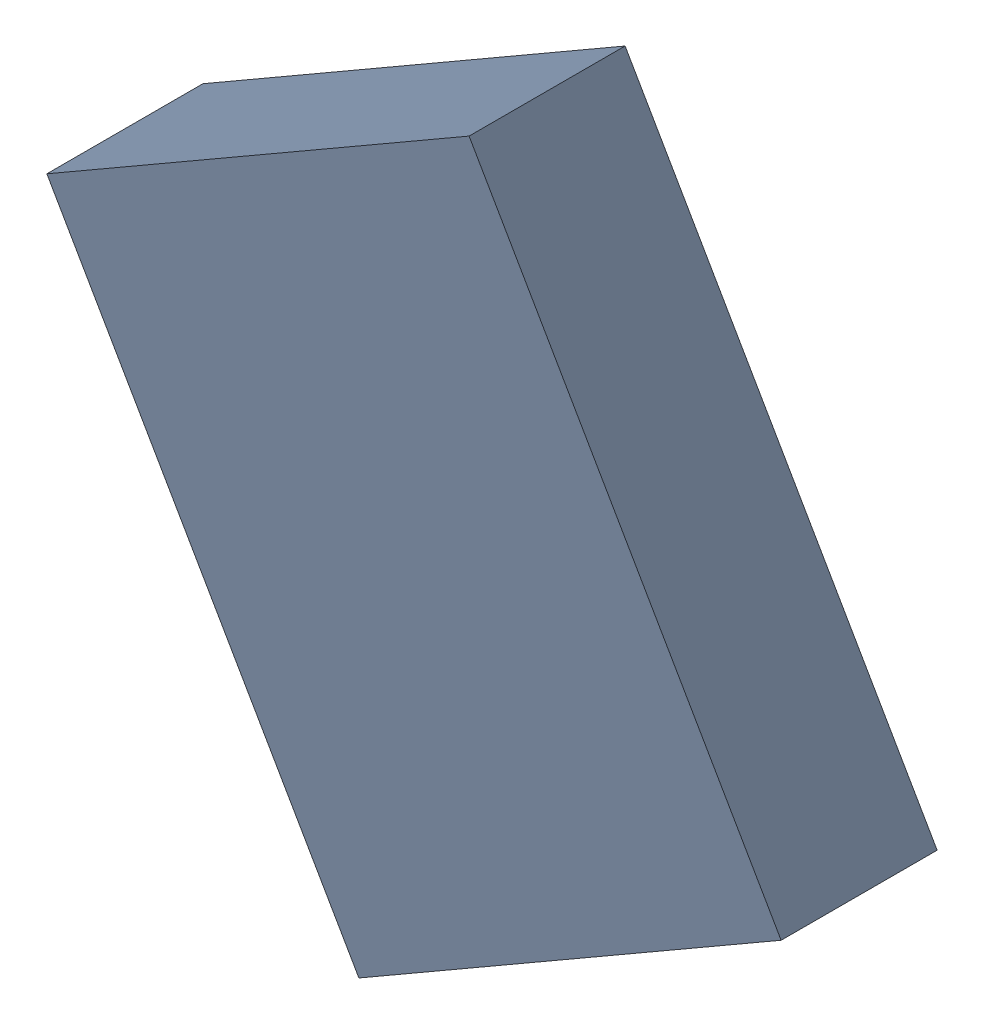
SolidWorks assembly X_TDA_1_TDA2, configuration Standard. Lengths in mm.
Overall size (3.77 4.02 0.8).
2 component instances, 1 part files, 0 mates.
Components (placement in the parent):
- 668293664-1: 668293664 [Standard] at (34.8045 23.5121 0) size (3.77 4.02 0.8)
  - Extruded_2-1: Extruded_2 [Standard] at origin size (3.77 4.02 0.8)
